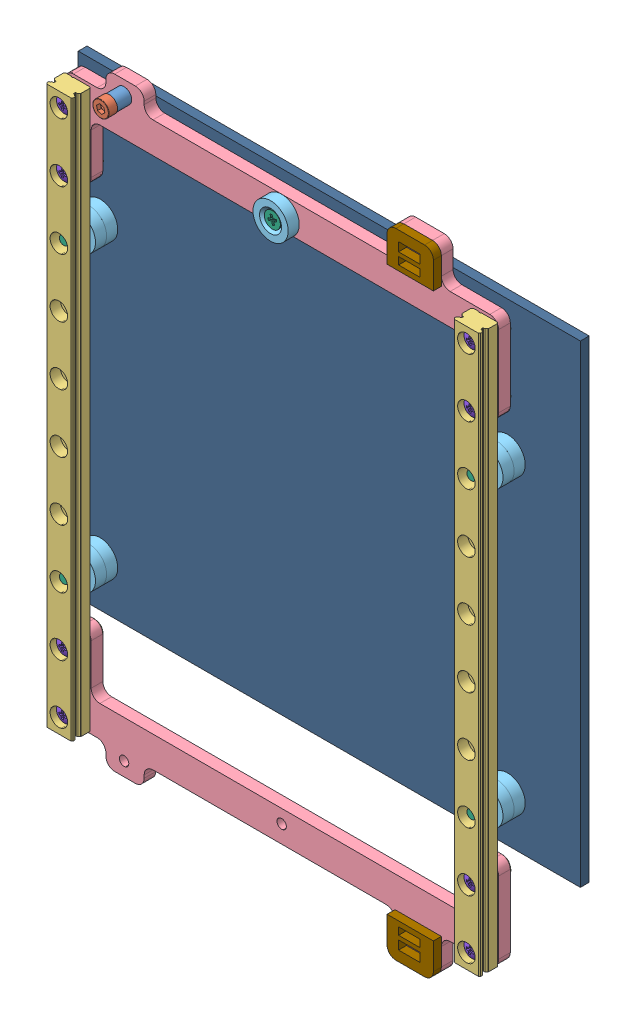
SolidWorks assembly Bed Assembly unifyed, configuration Default. Lengths in mm.
Overall size (172.3 216.19 18.58).
40 component instances, 10 part files, 74 mates.
Components (placement in the parent):
- Mini CF200x300WP1 TF4 Acrilyc 5mm washer^TF4 x axis-10: Mini CF200x300WP1 TF4 Acrilyc 5mm washer^TF4 x axis [Default] at (-314.9029 386.1623 -18.4872) x (0.617939 0.786226 0) z (0 0 -1) size (5.2 5.2 5)
- socket head cap screw_iso-23: socket head cap screw_iso [ISO 4762 M3 x 10 --- 10N] at (-53.7661 182.7645 -15.4872) x (0 0 -1) z (0.972645 0.232298 0) size (13 5.5 5.5)
- Mini CF200x300WP1 TF4 Y Track-1: Mini CF200x300WP1 TF4 Y Track [Default] at (69.4697 41.9676 -16.9872) x (1 0 0) z (0 -1 0) size (9 6.59 190)
- Mini CF200x300WP1 TF4 Y Track-2: Mini CF200x300WP1 TF4 Y Track [Default] at (-69.5303 41.9676 -16.9872) x (1 0 0) z (0 -1 0) size (9 6.59 190)
- TABLE2-1: TABLE2 [Valor predeterminado] at (5.3558 -55.8869 -23.4872) x (1 0 0) z (0 0 -1) size (148 42.68 4)
- TABLE2-2: TABLE2 [Valor predeterminado] at (5.3558 224.8221 -27.4872) size (148 42.68 4)
- Mini CF  Magnet 12X3.79mm-1: Magnet (12x3.79mm) [Default] at (-23.6484 175.0946 -19.6972) x (0.239858 0.970808 0) z (0 0 -1) size (12 12 3.79)
- ISO 7046-1 - M3 x 12 - Z --- 12N-1: ISO 7046-1 - M3 x 12 - Z --- 12N [ISO 7046-1 - M3 x 6 - Z --- 6N] at (-0.0303 174.4676 -20.2972) x (0 0 -1) z (-0.957254 -0.289249 0) size (6 5.5 5.5)
- Mini CF  Magnet 12X3.79mm-2: Magnet (12x3.79mm) [Default] at (-47.1634 126.8566 -27.2772) x (0.112075 0.9937 0) z (0 0 1) size (12 12 3.79)
- Mini CF  Magnet 12X3.79mm-3: Magnet (12x3.79mm) [Default] at (92.276 128.2967 -27.2772) x (0.048553 0.998821 0) z (0 0 1) size (12 12 3.79)
- Mini CF  Magnet 12X3.79mm-4: Magnet (12x3.79mm) [Default] at (49.5168 21.815 -27.2772) x (0.703858 -0.710341 0) z (0 0 1) size (12 12 3.79)
- Mini CF  Magnet 12X3.79mm-5: Magnet (12x3.79mm) [Default] at (-65.4998 11.1875 -27.2772) x (0.926004 0.377513 0) z (0 0 1) size (12 12 3.79)
- Mini CF  Magnet 12X3.79mm-6: Magnet (12x3.79mm) [Default] at (-89.3394 147.3441 -27.2772) x (0.711812 0.70237 0) z (0 0 -1) size (12 12 3.79)
- Mini CF  Magnet 12X3.79mm-7: Magnet (12x3.79mm) [Default] at (-85.9131 17.4438 -27.2772) x (-0.555454 0.831547 0) z (0 0 -1) size (12 12 3.79)
- Mini CF  Magnet 12X3.79mm-8: Magnet (12x3.79mm) [Default] at (57.7453 113.9555 -27.2772) x (-0.741869 0.670544 0) z (0 0 -1) size (12 12 3.79)
- Mini CF  Magnet 12X3.79mm-9: Magnet (12x3.79mm) [Default] at (53.0869 17.4438 -27.2772) x (-0.555454 0.831547 0) z (0 0 -1) size (12 12 3.79)
- hex thin nut chamfered gradeab_iso-1: hex thin nut chamfered gradeab_iso [Hexagon Thin Nut ISO - 4035 - M3 - N] at (69.4697 -5.5324 -29.2872) x (-0.70279 -0.711397 0) z (0 0 -1) size (5.5 6.35 1.8)
- hex thin nut chamfered gradeab_iso-2: hex thin nut chamfered gradeab_iso [Hexagon Thin Nut ISO - 4035 - M3 - N] at (-69.5303 -5.5324 -29.2872) x (0.473783 -0.880641 0) z (0 0 -1) size (5.5 6.35 1.8)
- hex thin nut chamfered gradeab_iso-3: hex thin nut chamfered gradeab_iso [Hexagon Thin Nut ISO - 4035 - M3 - N] at (69.4697 14.4676 -29.2872) x (-0.790707 0.612195 0) z (0 0 -1) size (5.5 6.35 1.8)
- hex thin nut chamfered gradeab_iso-4: hex thin nut chamfered gradeab_iso [Hexagon Thin Nut ISO - 4035 - M3 - N] at (-69.5303 14.4676 -29.2872) x (-0.98093 -0.194364 0) z (0 0 -1) size (5.5 6.35 1.8)
- hex thin nut chamfered gradeab_iso-5: hex thin nut chamfered gradeab_iso [Hexagon Thin Nut ISO - 4035 - M3 - N] at (69.4697 154.4676 -29.2872) x (0.923728 0.383049 0) z (0 0 -1) size (5.5 6.35 1.8)
- hex thin nut chamfered gradeab_iso-6: hex thin nut chamfered gradeab_iso [Hexagon Thin Nut ISO - 4035 - M3 - N] at (69.4697 174.4676 -29.2872) x (0.923728 0.383049 0) z (0 0 -1) size (5.5 6.35 1.8)
- hex thin nut chamfered gradeab_iso-7: hex thin nut chamfered gradeab_iso [Hexagon Thin Nut ISO - 4035 - M3 - N] at (-53.7661 182.7645 -29.2872) x (-0.886903 0.461956 0) z (0 0 -1) size (5.5 6.35 1.8)
- hex thin nut chamfered gradeab_iso-8: hex thin nut chamfered gradeab_iso [Hexagon Thin Nut ISO - 4035 - M3 - N] at (-69.5303 174.4676 -29.2872) x (0.923728 0.383049 0) z (0 0 -1) size (5.5 6.35 1.8)
- hex thin nut chamfered gradeab_iso-9: hex thin nut chamfered gradeab_iso [Hexagon Thin Nut ISO - 4035 - M3 - N] at (-69.5303 154.4676 -29.2872) x (0.923728 0.383049 0) z (0 0 -1) size (5.5 6.35 1.8)
- ISO 7045 - M4 x 12 - Z --- 12N-2: ISO 7045 - M4 x 12 - Z --- 12N [ISO 7045 - M3 x 8 - Z --- 8N] at (69.4697 154.4676 -18.0872) x (0 0 -1) z (1 0 0) size (10.35 5.6 5.6)
- ISO 7045 - M4 x 12 - Z --- 12N-3: ISO 7045 - M4 x 12 - Z --- 12N [ISO 7045 - M3 x 8 - Z --- 8N] at (-69.5303 174.4676 -18.0872) x (0 0 -1) z (1 0 0) size (10.35 5.6 5.6)
- ISO 7045 - M4 x 12 - Z --- 12N-4: ISO 7045 - M4 x 12 - Z --- 12N [ISO 7045 - M3 x 8 - Z --- 8N] at (-69.5303 154.4676 -18.0872) x (0 0 -1) z (1 0 0) size (10.35 5.6 5.6)
- ISO 7045 - M4 x 12 - Z --- 12N-5: ISO 7045 - M4 x 12 - Z --- 12N [ISO 7045 - M3 x 8 - Z --- 8N] at (-69.5303 14.4676 -18.0872) x (0 0 -1) z (1 0 0) size (10.35 5.6 5.6)
- ISO 7045 - M4 x 12 - Z --- 12N-6: ISO 7045 - M4 x 12 - Z --- 12N [ISO 7045 - M3 x 8 - Z --- 8N] at (-69.5303 -5.5324 -18.0872) x (0 0 -1) z (1 0 0) size (10.35 5.6 5.6)
- ISO 7045 - M4 x 12 - Z --- 12N-7: ISO 7045 - M4 x 12 - Z --- 12N [ISO 7045 - M3 x 8 - Z --- 8N] at (69.4697 -5.5324 -18.0872) x (0 0 -1) z (-0.140617 -0.990064 0) size (10.35 5.6 5.6)
- ISO 7045 - M4 x 12 - Z --- 12N-8: ISO 7045 - M4 x 12 - Z --- 12N [ISO 7045 - M3 x 8 - Z --- 8N] at (69.4697 14.4676 -18.0872) x (0 0 -1) z (1 0 0) size (10.35 5.6 5.6)
- ISO 7045 - M4 x 12 - Z --- 12N-9: ISO 7045 - M4 x 12 - Z --- 12N [ISO 7045 - M3 x 8 - Z --- 8N] at (69.4697 174.4676 -18.0872) x (0 0 -1) z (1 0 0) size (10.35 5.6 5.6)
- ISO 7046-1 - M3 x 12 - Z --- 12N-2: ISO 7046-1 - M3 x 12 - Z --- 12N [ISO 7046-1 - M3 x 8 - Z --- 8N] at (69.4697 134.4676 -26.6772) x (0 0 1) z (-0.99981 0.0195 0) size (8 5.5 5.5)
- ISO 7046-1 - M3 x 12 - Z --- 12N-3: ISO 7046-1 - M3 x 12 - Z --- 12N [ISO 7046-1 - M3 x 8 - Z --- 8N] at (-69.5303 134.4676 -26.6772) x (0 0 1) z (-0.999984 -0.005729 0) size (8 5.5 5.5)
- ISO 7046-1 - M3 x 12 - Z --- 12N-4: ISO 7046-1 - M3 x 12 - Z --- 12N [ISO 7046-1 - M3 x 8 - Z --- 8N] at (-69.5303 34.4676 -26.6772) x (0 0 1) z (-0.999927 0.012099 0) size (8 5.5 5.5)
- ISO 7046-1 - M3 x 12 - Z --- 12N-5: ISO 7046-1 - M3 x 12 - Z --- 12N [ISO 7046-1 - M3 x 8 - Z --- 8N] at (69.4697 34.4676 -26.6772) x (0 0 1) z (-1 0.00035 0) size (8 5.5 5.5)
- BED SPACER-3: BED SPACER [Default] at (16.3993 -224.961 -23.4872) x (-1 0 0) z (0 0 1) size (15.78 12.09 2.72)
- BED SPACER-4: BED SPACER [Default] at (16.3993 393.8962 -20.7678) x (-1 0 0) z (0 0 -1) size (15.78 12.09 2.72)
- Copy of glassbed-2: Copy of glassbed [Default] at (37.6504 -344.1579 -31.0672) x (1 0 0) z (0 0 -1) size (171.28 161.41 3)
Mates (geometry in assembly coordinates):
- Concentric39991: concentric anti-aligned: cylinder of Mini CF200x300WP1 TF4 Acrilyc 5mm washer^TF4 x axis-10 through (-53.7661 182.7645 -23.4872) axis (0 0 -1) radius 1.6; circle of socket head cap screw_iso-23
- Coincident787052: coincident anti-aligned: plane of Mini CF200x300WP1 TF4 Acrilyc 5mm washer^TF4 x axis-10 through (-53.7661 182.7645 -18.4872) normal (0 0 1); plane of socket head cap screw_iso-23 through (-54.4049 185.4393 -18.4872) normal (0 0 -1)
- Coincidente200: coincident aligned: plane of Mini CF200x300WP1 TF4 Y Track-2 through (-77.2131 -10.5324 -13.4872) normal (0 -1 0); plane of Mini CF200x300WP1 TF4 Y Track-1 through (61.7869 -10.5324 -13.4872) normal (0 -1 0)
- Coincidente225: coincident anti-aligned: plane of Mini CF200x300WP1 TF4 Y Track-2 through (-65.4303 341.9676 -23.4872) normal (0 0 -1); plane of TABLE2-1 through (-91.0935 177.4676 -23.4872) normal (0 0 1)
- Concêntrico99: concentric anti-aligned: cylinder of socket head cap screw_iso-23 through (-53.7661 182.7645 16.2628) axis (0 0 1) radius 1.5; cylinder of TABLE2-1 through (-53.7661 182.7645 -27.4872) axis (0 0 -1) radius 1.6
- Coincidente229: coincident anti-aligned: plane of Mini CF200x300WP1 TF4 Acrilyc 5mm washer^TF4 x axis-10 through (-53.7661 182.7645 -23.4872) normal (0 0 -1); plane of TABLE2-1 through (-91.0935 177.4676 -23.4872) normal (0 0 1)
- Coincident16: coincident anti-aligned: plane of Mini CF200x300WP1 TF4 Y Track-2 through (-65.4303 341.9676 -23.4872) normal (0 0 -1); plane of TABLE2-2 through (-91.0935 -8.5324 -23.4872) normal (0 0 1)
- Coincident787053: coincident anti-aligned: plane of TABLE2-1 through (-91.0935 177.4676 -23.4872) normal (0 0 1); plane of Mini CF  Magnet 12X3.79mm-1 through (-0.0303 174.4676 -23.4872) normal (0 0 -1)
- Concentric401119: concentric aligned: circle of TABLE2-1; circle of Mini CF  Magnet 12X3.79mm-1
- Coincident787054: coincident aligned: cone of Mini CF  Magnet 12X3.79mm-1 through (-0.0303 174.4676 -19.6972) axis (0 0 -1); cone of ISO 7046-1 - M3 x 12 - Z --- 12N-1 through (-0.0303 174.4676 -20.6972) axis (0 0 -1)
- Coincident787055: coincident anti-aligned: plane of Mini CF200x300WP1 TF4 Y Track-2 through (-65.4303 341.9676 -23.4872) normal (0 0 -1); plane of Mini CF  Magnet 12X3.79mm-2 through (-69.5303 134.4676 -23.4872) normal (0 0 1)
- Concentric401121: concentric aligned: cylinder of Mini CF200x300WP1 TF4 Y Track-2 through (-69.5303 134.4676 -20.2372) axis (0 0 -1) radius 1.75; cylinder of Mini CF  Magnet 12X3.79mm-2 through (-69.5303 134.4676 -23.4872) axis (0 0 -1) radius 1.62
- Coincident20: coincident anti-aligned: plane of Mini CF  Magnet 12X3.79mm-2 through (-69.5303 134.4676 -27.2772) normal (0 0 -1); plane of Mini CF  Magnet 12X3.79mm-6 through (-69.5303 134.4676 -27.2772) normal (0 0 1)
- Coincident21: coincident aligned: circle of Mini CF  Magnet 12X3.79mm-2; cylinder of Mini CF  Magnet 12X3.79mm-6 through (-69.5303 134.4676 -31.0672) axis (0 0 1) radius 6
- Coincident17: coincident anti-aligned: plane of Mini CF200x300WP1 TF4 Y Track-1 through (73.5697 341.9676 -23.4872) normal (0 0 -1); plane of Mini CF  Magnet 12X3.79mm-3 through (69.4697 134.4676 -23.4872) normal (0 0 1)
- Concentric401122: concentric aligned: cylinder of Mini CF200x300WP1 TF4 Y Track-1 through (69.4697 134.4676 -20.2372) axis (0 0 -1) radius 1.75; cylinder of Mini CF  Magnet 12X3.79mm-3 through (69.4697 134.4676 -23.4872) axis (0 0 -1) radius 1.62
- Coincident23: coincident anti-aligned: plane of Mini CF  Magnet 12X3.79mm-3 through (69.4697 134.4676 -27.2772) normal (0 0 -1); plane of Mini CF  Magnet 12X3.79mm-8 through (69.4697 134.4676 -27.2772) normal (0 0 1)
- Concentric401123: concentric anti-aligned: cylinder of Mini CF  Magnet 12X3.79mm-3 through (69.4697 134.4676 -23.4872) axis (0 0 -1) radius 6; cylinder of Mini CF  Magnet 12X3.79mm-8 through (69.4697 134.4676 -31.0672) axis (0 0 1) radius 6
- Coincident18: coincident anti-aligned: plane of Mini CF200x300WP1 TF4 Y Track-1 through (73.5697 341.9676 -23.4872) normal (0 0 -1); plane of Mini CF  Magnet 12X3.79mm-4 through (69.4697 34.4676 -23.4872) normal (0 0 1)
- Concentric401124: concentric aligned: cylinder of Mini CF200x300WP1 TF4 Y Track-1 through (69.4697 34.4676 -20.2372) axis (0 0 -1) radius 1.75; cylinder of Mini CF  Magnet 12X3.79mm-4 through (69.4697 34.4676 -23.4872) axis (0 0 -1) radius 1.62
- Coincident24: coincident anti-aligned: plane of Mini CF  Magnet 12X3.79mm-4 through (69.4697 34.4676 -27.2772) normal (0 0 -1); plane of Mini CF  Magnet 12X3.79mm-9 through (69.4697 34.4676 -27.2772) normal (0 0 1)
- Concentric401125: concentric anti-aligned: cylinder of Mini CF  Magnet 12X3.79mm-4 through (69.4697 34.4676 -23.4872) axis (0 0 -1) radius 6; cylinder of Mini CF  Magnet 12X3.79mm-9 through (69.4697 34.4676 -31.0672) axis (0 0 1) radius 6
- Coincident19: coincident anti-aligned: plane of Mini CF200x300WP1 TF4 Y Track-2 through (-65.4303 341.9676 -23.4872) normal (0 0 -1); plane of Mini CF  Magnet 12X3.79mm-5 through (-69.5303 34.4676 -23.4872) normal (0 0 1)
- Concentric401126: concentric aligned: cylinder of Mini CF200x300WP1 TF4 Y Track-2 through (-69.5303 34.4676 -20.2372) axis (0 0 -1) radius 1.75; cylinder of Mini CF  Magnet 12X3.79mm-5 through (-69.5303 34.4676 -23.4872) axis (0 0 -1) radius 1.62
- Coincident22: coincident anti-aligned: plane of Mini CF  Magnet 12X3.79mm-5 through (-69.5303 34.4676 -27.2772) normal (0 0 -1); plane of Mini CF  Magnet 12X3.79mm-7 through (-69.5303 34.4676 -27.2772) normal (0 0 1)
- Concentric401127: concentric anti-aligned: cylinder of Mini CF  Magnet 12X3.79mm-5 through (-69.5303 34.4676 -23.4872) axis (0 0 -1) radius 6; cylinder of Mini CF  Magnet 12X3.79mm-7 through (-69.5303 34.4676 -31.0672) axis (0 0 1) radius 6
- Coincident787058: coincident anti-aligned: plane of TABLE2-2 through (-91.0935 -8.5324 -27.4872) normal (0 0 -1); plane of hex thin nut chamfered gradeab_iso-1 through (67.2107 -3.3007 -27.4872) normal (0 0 1)
- Coincident787059: coincident anti-aligned: plane of TABLE2-2 through (-91.0935 -8.5324 -27.4872) normal (0 0 -1); plane of hex thin nut chamfered gradeab_iso-2 through (-72.3267 -7.0369 -27.4872) normal (0 0 1)
- Concentric401130: concentric anti-aligned: cylinder of TABLE2-2 through (69.4697 14.4676 -23.4872) axis (0 0 1) radius 1.6; cylinder of hex thin nut chamfered gradeab_iso-3 through (69.4697 14.4676 -4.2497) axis (0 0 -1) radius 1.5
- Coincident787060: coincident anti-aligned: plane of TABLE2-2 through (-91.0935 -8.5324 -27.4872) normal (0 0 -1); plane of hex thin nut chamfered gradeab_iso-3 through (71.4137 16.9784 -27.4872) normal (0 0 1)
- Concentric401131: concentric anti-aligned: cylinder of TABLE2-2 through (-69.5303 14.4676 -23.4872) axis (0 0 1) radius 1.6; cylinder of hex thin nut chamfered gradeab_iso-4 through (-69.5303 14.4676 -4.2497) axis (0 0 -1) radius 1.5
- Coincident787061: coincident anti-aligned: plane of TABLE2-2 through (-91.0935 -8.5324 -27.4872) normal (0 0 -1); plane of hex thin nut chamfered gradeab_iso-4 through (-70.1475 17.5825 -27.4872) normal (0 0 1)
- Concentric401132: concentric aligned: cylinder of TABLE2-1 through (69.4697 154.4676 -27.4872) axis (0 0 -1) radius 1.6; cylinder of hex thin nut chamfered gradeab_iso-5 through (69.4697 154.4676 -4.2497) axis (0 0 -1) radius 1.5
- Coincident787062: coincident anti-aligned: plane of TABLE2-1 through (-91.0935 177.4676 -27.4872) normal (0 0 -1); plane of hex thin nut chamfered gradeab_iso-5 through (70.686 151.5344 -27.4872) normal (0 0 1)
- Coincident787063: coincident anti-aligned: plane of TABLE2-1 through (-91.0935 177.4676 -27.4872) normal (0 0 -1); plane of hex thin nut chamfered gradeab_iso-6 through (70.686 171.5344 -27.4872) normal (0 0 1)
- Concentric401134: concentric anti-aligned: cylinder of socket head cap screw_iso-23 through (-53.7661 182.7645 16.2628) axis (0 0 1) radius 1.5; cylinder of hex thin nut chamfered gradeab_iso-7 through (-53.7661 182.7645 -4.2497) axis (0 0 -1) radius 1.5
- Coincident787064: coincident anti-aligned: plane of TABLE2-1 through (-91.0935 177.4676 -27.4872) normal (0 0 -1); plane of hex thin nut chamfered gradeab_iso-7 through (-52.2992 185.5808 -27.4872) normal (0 0 1)
- Coincident787065: coincident anti-aligned: plane of TABLE2-1 through (-91.0935 177.4676 -27.4872) normal (0 0 -1); plane of hex thin nut chamfered gradeab_iso-8 through (-68.314 171.5344 -27.4872) normal (0 0 1)
- Concentric401136: concentric aligned: cylinder of TABLE2-1 through (-69.5303 154.4676 -27.4872) axis (0 0 -1) radius 1.6; cylinder of hex thin nut chamfered gradeab_iso-9 through (-69.5303 154.4676 -4.2497) axis (0 0 -1) radius 1.5
- Coincident787066: coincident anti-aligned: plane of TABLE2-1 through (-91.0935 177.4676 -27.4872) normal (0 0 -1); plane of hex thin nut chamfered gradeab_iso-9 through (-68.314 151.5344 -27.4872) normal (0 0 1)
- Concentric401138: concentric anti-aligned: cylinder of Mini CF200x300WP1 TF4 Y Track-1 through (69.4697 154.4676 -20.2372) axis (0 0 -1) radius 1.75; cylinder of ISO 7045 - M4 x 12 - Z --- 12N-2 through (69.4697 154.4676 7.3128) axis (0 0 1) radius 2.8
- Coincident787068: coincident anti-aligned: plane of Mini CF200x300WP1 TF4 Y Track-1 through (69.4697 154.4676 -20.4872) normal (0 0 1); plane of ISO 7045 - M4 x 12 - Z --- 12N-2 through (69.4697 155.9676 -20.4872) normal (0 0 -1)
- Concentric401139: concentric anti-aligned: cylinder of Mini CF200x300WP1 TF4 Y Track-2 through (-69.5303 174.4676 -20.2372) axis (0 0 -1) radius 1.75; cylinder of ISO 7045 - M4 x 12 - Z --- 12N-3 through (-69.5303 174.4676 7.3128) axis (0 0 1) radius 2.8
- Coincident787069: coincident anti-aligned: plane of Mini CF200x300WP1 TF4 Y Track-2 through (-69.5303 174.4676 -20.4872) normal (0 0 1); plane of ISO 7045 - M4 x 12 - Z --- 12N-3 through (-69.5303 175.9676 -20.4872) normal (0 0 -1)
- Concentric401140: concentric anti-aligned: cylinder of Mini CF200x300WP1 TF4 Y Track-2 through (-69.5303 154.4676 -18.2372) axis (0 0 -1) radius 3; cylinder of ISO 7045 - M4 x 12 - Z --- 12N-4 through (-69.5303 154.4676 7.3128) axis (0 0 1) radius 2.8
- Coincident787070: coincident anti-aligned: plane of Mini CF200x300WP1 TF4 Y Track-2 through (-69.5303 154.4676 -20.4872) normal (0 0 1); plane of ISO 7045 - M4 x 12 - Z --- 12N-4 through (-69.5303 155.9676 -20.4872) normal (0 0 -1)
- Concentric401141: concentric anti-aligned: cylinder of Mini CF200x300WP1 TF4 Y Track-2 through (-69.5303 14.4676 -18.2372) axis (0 0 -1) radius 3; cylinder of ISO 7045 - M4 x 12 - Z --- 12N-5 through (-69.5303 14.4676 7.3128) axis (0 0 1) radius 2.8
- Coincident787071: coincident anti-aligned: plane of Mini CF200x300WP1 TF4 Y Track-2 through (-69.5303 14.4676 -20.4872) normal (0 0 1); plane of ISO 7045 - M4 x 12 - Z --- 12N-5 through (-69.5303 15.9676 -20.4872) normal (0 0 -1)
- Concentric401142: concentric anti-aligned: cylinder of Mini CF200x300WP1 TF4 Y Track-2 through (-69.5303 -5.5324 -18.2372) axis (0 0 -1) radius 3; cylinder of ISO 7045 - M4 x 12 - Z --- 12N-6 through (-69.5303 -5.5324 7.3128) axis (0 0 1) radius 2.8
- Coincident787072: coincident anti-aligned: plane of Mini CF200x300WP1 TF4 Y Track-2 through (-69.5303 -5.5324 -20.4872) normal (0 0 1); plane of ISO 7045 - M4 x 12 - Z --- 12N-6 through (-69.5303 -4.0324 -20.4872) normal (0 0 -1)
- Concentric401143: concentric anti-aligned: cylinder of Mini CF200x300WP1 TF4 Y Track-1 through (69.4697 -5.5324 -20.2372) axis (0 0 -1) radius 1.75; cylinder of ISO 7045 - M4 x 12 - Z --- 12N-7 through (69.4697 -5.5324 7.3128) axis (0 0 1) radius 2.8
- Coincident787073: coincident anti-aligned: plane of Mini CF200x300WP1 TF4 Y Track-1 through (69.4697 -5.5324 -20.4872) normal (0 0 1); plane of ISO 7045 - M4 x 12 - Z --- 12N-7 through (70.9548 -5.7433 -20.4872) normal (0 0 -1)
- Concentric401144: concentric anti-aligned: cylinder of Mini CF200x300WP1 TF4 Y Track-1 through (69.4697 14.4676 -20.2372) axis (0 0 -1) radius 1.75; cylinder of ISO 7045 - M4 x 12 - Z --- 12N-8 through (69.4697 14.4676 7.3128) axis (0 0 1) radius 2.8
- Coincident787074: coincident anti-aligned: plane of Mini CF200x300WP1 TF4 Y Track-1 through (69.4697 14.4676 -20.4872) normal (0 0 1); plane of ISO 7045 - M4 x 12 - Z --- 12N-8 through (69.4697 15.9676 -20.4872) normal (0 0 -1)
- Concentric401145: concentric anti-aligned: cylinder of Mini CF200x300WP1 TF4 Y Track-1 through (69.4697 174.4676 -20.2372) axis (0 0 -1) radius 1.75; cylinder of ISO 7045 - M4 x 12 - Z --- 12N-9 through (69.4697 174.4676 7.3128) axis (0 0 1) radius 2.8
- Coincident787075: coincident anti-aligned: plane of Mini CF200x300WP1 TF4 Y Track-1 through (69.4697 174.4676 -20.4872) normal (0 0 1); plane of ISO 7045 - M4 x 12 - Z --- 12N-9 through (69.4697 175.9676 -20.4872) normal (0 0 -1)
- Coincident787076: coincident aligned: cone of Mini CF  Magnet 12X3.79mm-3 through (69.4697 134.4676 -27.2772) axis (0 0 1); cone of ISO 7046-1 - M3 x 12 - Z --- 12N-2 through (69.4697 134.4676 -26.2772) axis (0 0 1)
- Coincident787077: coincident aligned: cone of Mini CF  Magnet 12X3.79mm-2 through (-69.5303 134.4676 -27.2772) axis (0 0 1); cone of ISO 7046-1 - M3 x 12 - Z --- 12N-3 through (-69.5303 134.4676 -26.2772) axis (0 0 1)
- Coincident787078: coincident aligned: cone of Mini CF  Magnet 12X3.79mm-5 through (-69.5303 34.4676 -27.2772) axis (0 0 1); cone of ISO 7046-1 - M3 x 12 - Z --- 12N-4 through (-69.5303 34.4676 -26.2772) axis (0 0 1)
- Coincident787079: coincident aligned: cone of Mini CF  Magnet 12X3.79mm-4 through (69.4697 34.4676 -27.2772) axis (0 0 1); cone of ISO 7046-1 - M3 x 12 - Z --- 12N-5 through (69.4697 34.4676 -26.2772) axis (0 0 1)
- Coincident26: coincident anti-aligned: plane of TABLE2-1 through (-91.0935 177.4676 -23.4872) normal (0 0 1); plane of BED SPACER-3 through (51.4331 189.5611 -23.4872) normal (0 0 -1)
- Concentric401120: concentric anti-aligned: cylinder of TABLE2-1 through (51.4331 189.5611 -27.4872) axis (0 0 1) radius 3; cylinder of BED SPACER-3 through (51.4331 189.5611 -0.8854) axis (0 0 -1) radius 3
- Coincident27: coincident aligned: plane of TABLE2-1 through (54.4331 183.4676 -27.4872) normal (1 0 0); plane of BED SPACER-3 through (54.4331 189.5611 -0.8854) normal (1 0 0)
- Coincident787080: coincident anti-aligned: plane of TABLE2-2 through (-91.0935 -8.5324 -23.4872) normal (0 0 1); plane of BED SPACER-4 through (49.3179 40.9564 -23.4872) normal (0 0 -1)
- Concentric401146: concentric anti-aligned: circle of TABLE2-2; circle of BED SPACER-4
- Coincident29: coincident aligned: plane of TABLE2-2 through (38.6515 -14.5324 -23.4872) normal (-1 0 0); plane of BED SPACER-4 through (38.6515 -11.5324 -43.3696) normal (-1 0 0)
- Concentric401149: concentric anti-aligned: cylinder of hex thin nut chamfered gradeab_iso-4 through (-69.5303 14.4676 -27.4872) axis (0 0 -1) radius 1.25; cylinder of ISO 7045 - M4 x 12 - Z --- 12N-5 through (-69.5303 14.4676 7.3128) axis (0 0 1) radius 1.5
- Concentric401150: concentric anti-aligned: cylinder of hex thin nut chamfered gradeab_iso-3 through (69.4697 14.4676 -27.4872) axis (0 0 -1) radius 1.25; cylinder of ISO 7045 - M4 x 12 - Z --- 12N-8 through (69.4697 14.4676 7.3128) axis (0 0 1) radius 1.5
- Concentric401151: concentric anti-aligned: cylinder of hex thin nut chamfered gradeab_iso-1 through (69.4697 -5.5324 -27.4872) axis (0 0 -1) radius 1.25; cylinder of ISO 7045 - M4 x 12 - Z --- 12N-7 through (69.4697 -5.5324 7.3128) axis (0 0 1) radius 1.5
- Concentric401152: concentric anti-aligned: cylinder of hex thin nut chamfered gradeab_iso-2 through (-69.5303 -5.5324 -27.4872) axis (0 0 -1) radius 1.25; cylinder of ISO 7045 - M4 x 12 - Z --- 12N-6 through (-69.5303 -5.5324 7.3128) axis (0 0 1) radius 1.5
- Concentric401154: concentric anti-aligned: cylinder of TABLE2-1 through (69.4697 174.4676 -27.4872) axis (0 0 -1) radius 1.6; cylinder of ISO 7045 - M4 x 12 - Z --- 12N-9 through (69.4697 174.4676 7.3128) axis (0 0 1) radius 1.5
- Coincident25: coincident anti-aligned: plane of Mini CF  Magnet 12X3.79mm-6 through (-69.5303 134.4676 -31.0672) normal (0 0 -1); plane of Copy of glassbed-2 through (37.6504 -344.1579 -31.0672) normal (0 0 1)
- Coincident787057: coincident aligned: plane of TABLE2-1 through (-43.9395 180.4676 -27.4872) normal (0 1 0); plane of Copy of glassbed-2 through (-77.0012 180.4676 -34.0672) normal (0 1 0)
- Distance7: distance = 20.3111 mm aligned: plane of Copy of glassbed-2 through (94.2807 180.4676 -34.0672) normal (1 0 0); plane of Mini CF200x300WP1 TF4 Y Track-1 through (73.9697 341.9676 -20.0455) normal (1 0 0)
